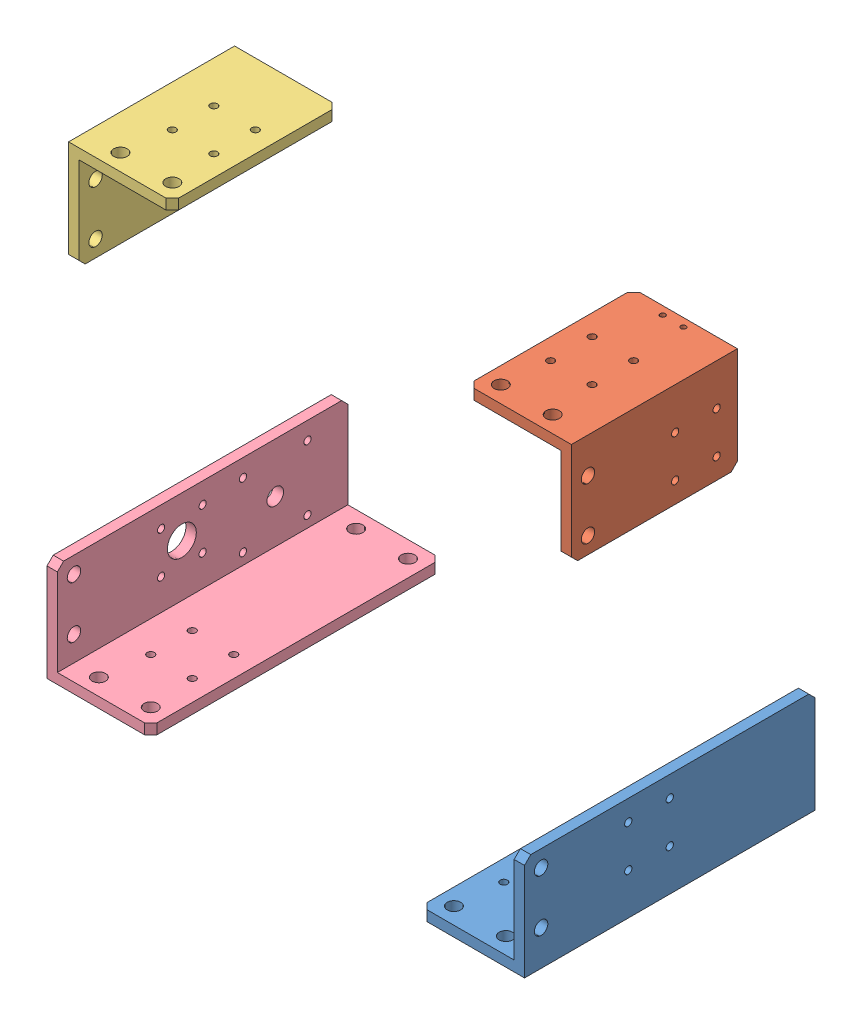
SolidWorks assembly Assieme1, configuration Default. Lengths in mm.
Overall size (266.76 243.35 154.04).
4 component instances, 4 part files, 0 mates.
Components (placement in the parent):
- Support plate 50x50 L.140mm Back-Left-1: Support plate 50x50 L.140mm Back-Left [Default] at (66.3413 -33.6687 -83.4632) x (0 1 0) z (0 0 1) size (50 50 140)
- Support plate 50x50 L.80mm Front-Left-1: Support plate 50x50 L.80mm Front-Left [Default] at (98.3276 209.6839 -14.0614) x (-1 0 0) z (0 0 1) size (50 50 80)
- Support plate 50x50 L.80mm Front-Right-1: Support plate 50x50 L.80mm Front-Right [Default] at (-155.6939 203.1493 -25.7707) x (0 -1 0) z (0 0 1) size (50 50 80)
- Support plate 50x50 L.140mm Rear-Right-1: Support plate 50x50 L.140mm Rear-Right [Default] at (-168.4337 -28.3773 -88.0983) size (50 50 140)
